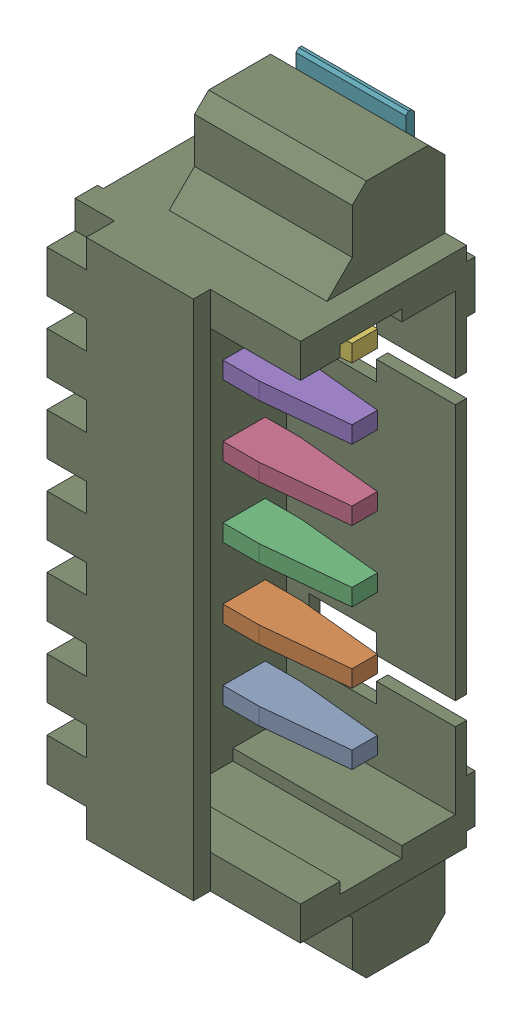
SolidWorks assembly J8, configuration Default. Lengths in mm.
Overall size (5.4 12.25 3.41).
10 component instances, 3 part files, 0 mates.
Components (placement in the parent):
- 653106131822-1: 653106131822 [Default] at (117.4 29.4749 1.69) x (0 1 0) z (0 0 1) size (12.25 5.4 3.41)
  - 6531xx131822_PIN-1: 6531xx131822_PIN [Default] at (-3.125 2.7 -0.425) x (1 0 0) z (0 -1 0) size (0.3 1.48 4.54)
  - 6531xx131822_PIN-2: 6531xx131822_PIN [Default] at (-1.875 2.7 -0.425) x (1 0 0) z (0 -1 0) size (0.3 1.48 4.54)
  - 6531xx131822_PIN-3: 6531xx131822_PIN [Default] at (-0.625 2.7 -0.425) x (1 0 0) z (0 -1 0) size (0.3 1.48 4.54)
  - 6531xx131822_PIN-4: 6531xx131822_PIN [Default] at (0.625 2.7 -0.425) x (1 0 0) z (0 -1 0) size (0.3 1.48 4.54)
  - 6531xx131822_PIN-5: 6531xx131822_PIN [Default] at (1.875 2.7 -0.425) x (1 0 0) z (0 -1 0) size (0.3 1.48 4.54)
  - 6531xx131822_PIN-6: 6531xx131822_PIN [Default] at (3.125 2.7 -0.425) x (1 0 0) z (0 -1 0) size (0.3 1.48 4.54)
  - 6531xx131822_PIN_FLANGE-1: 6531xx131822_PIN_FLANGE [Default] at (5 -0.045 -1.05) size (1.25 1.95 1.4)
  - 6531xx131822_PIN_FLANGE-2: 6531xx131822_PIN_FLANGE [Default] at (-5 -0.045 -1.05) x (-1 0 0) z (0 0 1) size (1.25 1.95 1.4)
  - 653106131822-1: 653106131822 [Default] at origin size (12.25 4.2 3.4)
